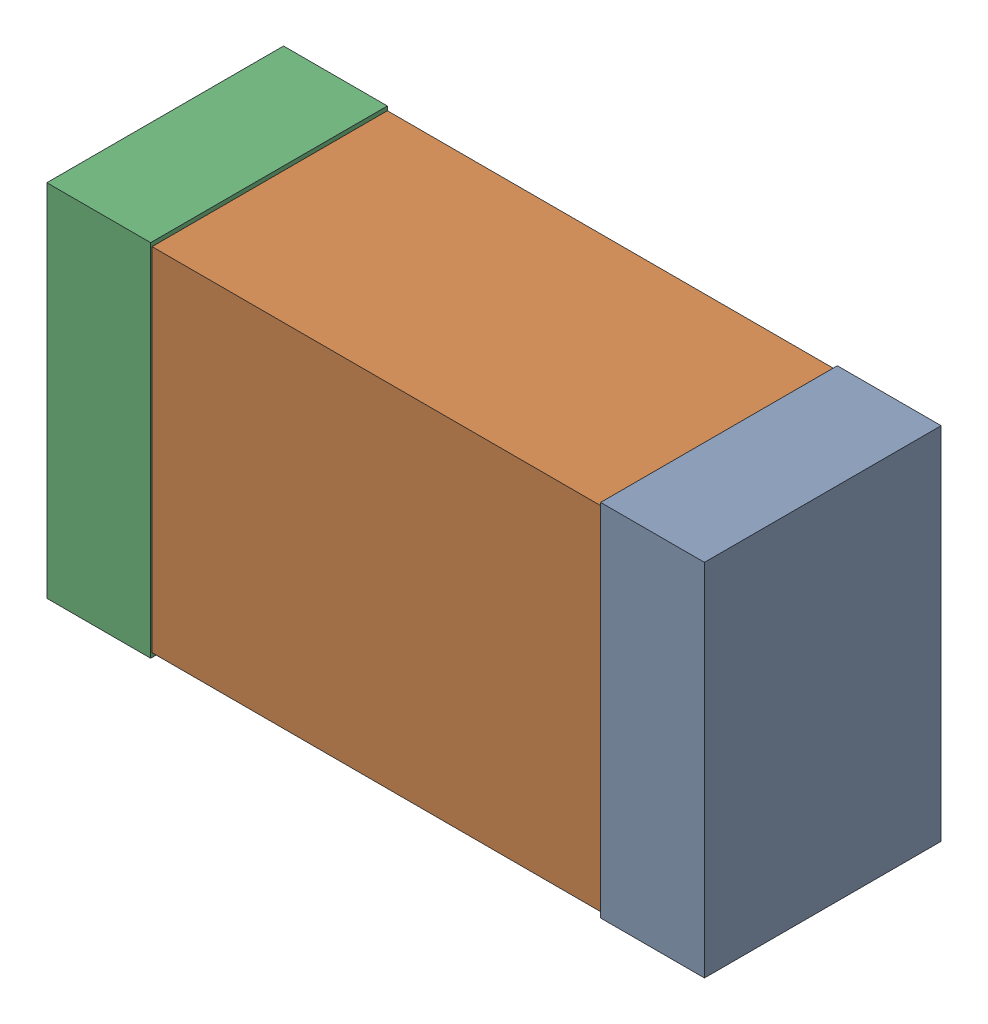
SolidWorks assembly Kanaloa_v2.0.0_Power_9, configuration Default. Lengths in mm.
Overall size (2.38 1.3 0.85).
6 component instances, 2 part files, 0 mates.
Components (placement in the parent):
- 352877648-1: 352877648 [Default] at (121.9256 104.0972 0) size (0.38 1.3 0.85)
  - Extruded_14-1: Extruded_14 [Default] at origin size (0.38 1.3 0.85)
- 352877904-1: 352877904 [Default] at (120.9256 104.0972 0) size (2.2 1.27 0.85)
  - Extruded_18-1: Extruded_18 [Default] at origin size (2.2 1.27 0.85)
- 352877648-2: 352877648 [Default] at (119.9256 104.0972 0) size (0.38 1.3 0.85)
  - Extruded_14-1: Extruded_14 [Default] at origin size (0.38 1.3 0.85)
